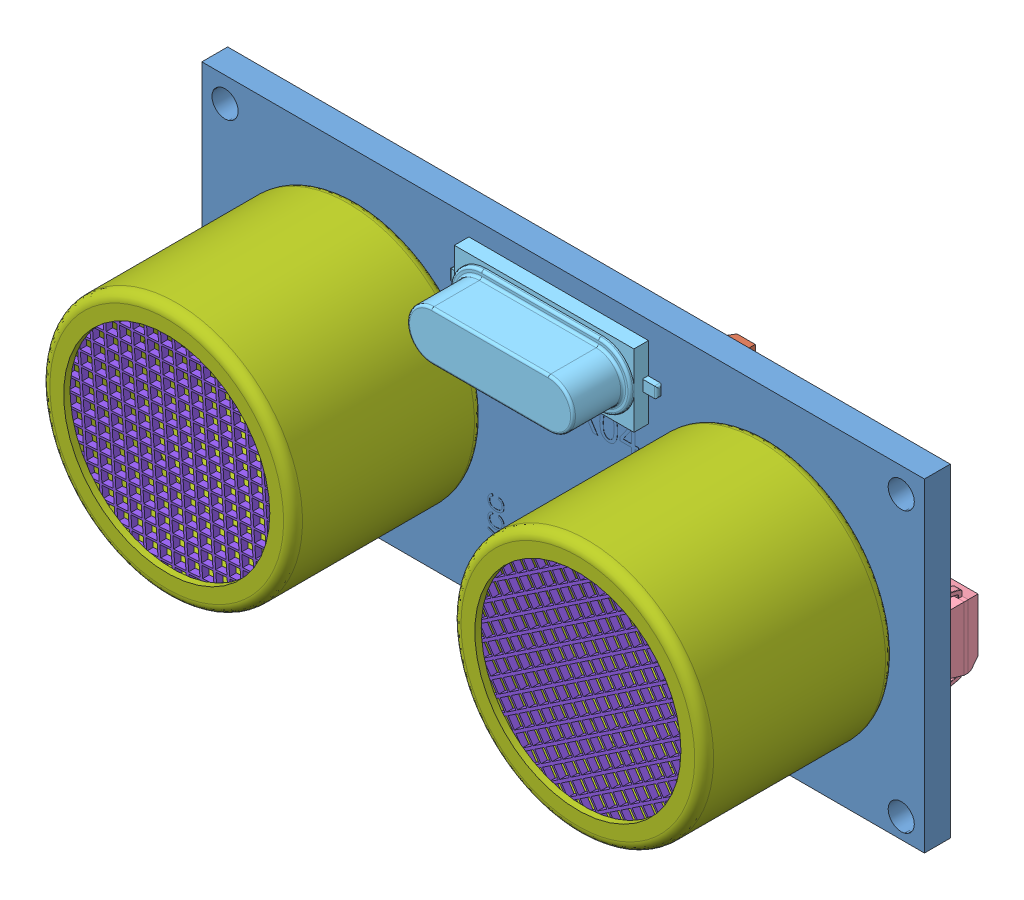
SolidWorks assembly HC-SR04, configuration Default. Lengths in mm.
Overall size (45.62 20.4 15.39).
49 component instances, 8 part files, 0 mates.
Components (placement in the parent):
- HC-SR04.stp-1: HC-SR04.stp [Default] at origin size (45.62 20.4 15.39)
  - Board.stp-1: Board.stp [Default] at (1.119 4.8754 1.6384) x (-1 0 0) z (0 0 -1) size (45.49 20.4 1.82)
  - SOT23.stp-1: SOT23.stp [Default] at (-8.8783 4.7543 -0.6372) x (-1 0 0) z (0 0 -1) size (3 2.25 1.22)
  - 0603 Resistor.stp-1: 0603 Resistor.stp [Default] at (-2.3118 -1.4161 0.0154) x (-1 0 0) z (0 0 -1) size (1.6 0.85 0.56)
  - SOT23.stp-2: SOT23.stp [Default] at (9.8161 12.8896 -0.6372) x (0 -1 0) z (0 0 -1) size (3 2.25 1.22)
  - SOIC16 narrow.stp-1: SOIC16 narrow.stp [Default] at (-17.261 3.8599 0.2628) x (0 1 0) z (0 0 -1) size (10.08 6.32 2.01)
  - SOIC16 narrow.stp-2: SOIC16 narrow.stp [Default] at (18.9536 5.248 0.2628) x (1 0 0) z (0 0 -1) size (10.08 6.32 2.01)
  - SOIC16 narrow.stp-3: SOIC16 narrow.stp [Default] at (0.4022 5.9646 0.2628) x (-1 0 0) z (0 0 -1) size (10.08 6.32 2.01)
  - Crystal Oscillator (SMD).stp-1: Crystal Oscillator (SMD).stp [Default] at (0.8376 11.6606 2.5528) x (-1 0 0) z (0 0 1) size (13.06 4.55 4.32)
  - 0603 Resistor.stp-2: 0603 Resistor.stp [Default] at (10.24 -3.1643 0.0154) x (1 0 0) z (0 0 -1) size (1.6 0.85 0.56)
  - 0603 Resistor.stp-3: 0603 Resistor.stp [Default] at (22.5315 0.1255 0.0154) x (-1 0 0) z (0 0 -1) size (1.6 0.85 0.56)
  - 0603 Resistor.stp-4: 0603 Resistor.stp [Default] at (12.7031 2.2363 0.0154) x (-1 0 0) z (0 0 -1) size (1.6 0.85 0.56)
  - 0603 Resistor.stp-5: 0603 Resistor.stp [Default] at (8.9722 2.0955 0.0154) x (-1 0 0) z (0 0 -1) size (1.6 0.85 0.56)
  - 0603 Resistor.stp-6: 0603 Resistor.stp [Default] at (5.593 0.1901 0.0154) x (-1 0 0) z (0 0 -1) size (1.6 0.85 0.56)
  - 0603 Resistor.stp-7: 0603 Resistor.stp [Default] at (2.0977 -1.5491 0.0154) x (-1 0 0) z (0 0 -1) size (1.6 0.85 0.56)
  - 0603 Resistor.stp-8: 0603 Resistor.stp [Default] at (16.3393 -2.5036 0.0154) x (0 -1 0) z (0 0 -1) size (1.6 0.85 0.56)
  - 0603 Resistor.stp-9: 0603 Resistor.stp [Default] at (14.5174 -2.327 0.0154) x (0 -1 0) z (0 0 -1) size (1.6 0.85 0.56)
  - 0603 Resistor.stp-10: 0603 Resistor.stp [Default] at (20.2482 13.8269 0.0154) x (0 -1 0) z (0 0 -1) size (1.6 0.85 0.56)
  - 0603 Resistor.stp-11: 0603 Resistor.stp [Default] at (16.6084 13.7494 0.0154) x (0 -1 0) z (0 0 -1) size (1.6 0.85 0.56)
  - 0603 Resistor.stp-12: 0603 Resistor.stp [Default] at (13.4039 13.6182 0.0154) x (0 -1 0) z (0 0 -1) size (1.6 0.85 0.56)
  - 0603 Resistor.stp-13: 0603 Resistor.stp [Default] at (-5.5775 5.4253 0.0154) x (0 -1 0) z (0 0 -1) size (1.6 0.85 0.56)
  - 0603 Resistor.stp-14: 0603 Resistor.stp [Default] at (-6.0754 13.0061 0.0154) x (-1 0 0) z (0 0 -1) size (1.6 0.85 0.56)
  - 0603 Resistor.stp-15: 0603 Resistor.stp [Default] at (7.0232 13.2296 0.0154) x (-1 0 0) z (0 0 -1) size (1.6 0.85 0.56)
  - 0603 Resistor.stp-16: 0603 Resistor.stp [Default] at (7.035 11.3464 0.0154) x (-1 0 0) z (0 0 -1) size (1.6 0.85 0.56)
  - 0603 Resistor.stp-17: 0603 Resistor.stp [Default] at (7.5662 9.8618 0.0154) x (1 0 0) z (0 0 -1) size (1.6 0.85 0.56)
  - 0603 Resistor.stp-18: 0603 Resistor.stp [Default] at (22.163 9.3525 0.0154) x (-1 0 0) z (0 0 -1) size (1.6 0.85 0.56)
  - 0603 Resistor.stp-19: 0603 Resistor.stp [Default] at (17.9102 9.4345 0.0154) x (-1 0 0) z (0 0 -1) size (1.6 0.85 0.56)
  - 0603 Resistor.stp-20: 0603 Resistor.stp [Default] at (11.8015 10.1266 0.0154) x (0 -1 0) z (0 0 -1) size (1.6 0.85 0.56)
  - 0603 Resistor.stp-21: 0603 Resistor.stp [Default] at (7.7458 7.0454 0.0154) x (0 -1 0) z (0 0 -1) size (1.6 0.85 0.56)
  - 0603 Capacitor.stp-1: 0603 Capacitor.stp [Default] at (22.5429 -1.4012 0.0154) x (-1 0 0) z (0 0 -1) size (1.6 0.84 0.84)
  - 0603 Capacitor.stp-2: 0603 Capacitor.stp [Default] at (19.868 -2.6031 0.0154) x (0 -1 0) z (0 0 -1) size (1.6 0.84 0.84)
  - 0603 Capacitor.stp-3: 0603 Capacitor.stp [Default] at (18.1521 -2.6737 0.0154) x (0 -1 0) z (0 0 -1) size (1.6 0.84 0.84)
  - 0603 Capacitor.stp-4: 0603 Capacitor.stp [Default] at (11.4714 0.1939 0.0154) x (0 -1 0) z (0 0 -1) size (1.6 0.84 0.84)
  - 0603 Capacitor.stp-5: 0603 Capacitor.stp [Default] at (18.4838 13.8207 0.0154) x (0 -1 0) z (0 0 -1) size (1.6 0.84 0.84)
  - 0603 Capacitor.stp-6: 0603 Capacitor.stp [Default] at (9.1746 0.0669 -0.8228) x (-1 0 0) z (0 1 0) size (1.6 0.84 0.84)
  - 0603 Capacitor.stp-7: 0603 Capacitor.stp [Default] at (9.1446 -1.7914 0.0154) x (-1 0 0) z (0 0 -1) size (1.6 0.84 0.84)
  - 0603 Capacitor.stp-8: 0603 Capacitor.stp [Default] at (12.4703 5.822 0.0154) x (-1 0 0) z (0 0 -1) size (1.6 0.84 0.84)
  - 0603 Capacitor.stp-9: 0603 Capacitor.stp [Default] at (9.5482 7.223 0.0154) x (0 -1 0) z (0 0 -1) size (1.6 0.84 0.84)
  - 0603 Capacitor.stp-10: 0603 Capacitor.stp [Default] at (2.0325 13.7229 0.0154) x (0 -1 0) z (0 0 -1) size (1.6 0.84 0.84)
  - 0603 Capacitor.stp-11: 0603 Capacitor.stp [Default] at (0.1063 12.1848 -0.8228) x (0 1 0) z (0 0 1) size (1.6 0.84 0.84)
  - 0603 Capacitor.stp-12: 0603 Capacitor.stp [Default] at (-6.0774 9.7534 0.0154) x (0 -1 0) z (0 0 -1) size (1.6 0.84 0.84)
  - 0603 Capacitor.stp-13: 0603 Capacitor.stp [Default] at (-11.2678 7.8616 0.0154) x (0 -1 0) z (0 0 -1) size (1.6 0.84 0.84)
  - 0603 Capacitor.stp-14: 0603 Capacitor.stp [Default] at (-11.2504 4.5025 0.0154) x (0 -1 0) z (0 0 -1) size (1.6 0.84 0.84)
  - 0603 Capacitor.stp-15: 0603 Capacitor.stp [Default] at (-16.048 12.0413 0.0154) x (0 -1 0) z (0 0 -1) size (1.6 0.84 0.84)
  - 0603 Capacitor.stp-16: 0603 Capacitor.stp [Default] at (-17.9858 12.0322 0.0154) x (0 -1 0) z (0 0 -1) size (1.6 0.84 0.84)
  - 0603 Capacitor.stp-17: 0603 Capacitor.stp [Default] at (-8.431 0.2239 0.0154) x (-1 0 0) z (0 0 -1) size (1.6 0.84 0.84)
  - Transducer.stp-1: Transducer.stp [Default] at (1.119 4.8754 1.6384) x (-1 0 0) z (0 0 -1) size (41.78 15.9 12.01)
  - Mesh.stp-1: Mesh.stp [Default] at (1.0621 5.8125 1.6384) x (-0.997371 -0.072467 0) z (0 0 -1) size (13.88 13.88 0.41)
  - Mesh.stp-2: Mesh.stp [Default] at (7.1073 15.456 24.4476) x (0.558295 -0.829642 0) z (0 0 1) size (13.88 13.88 0.41)
